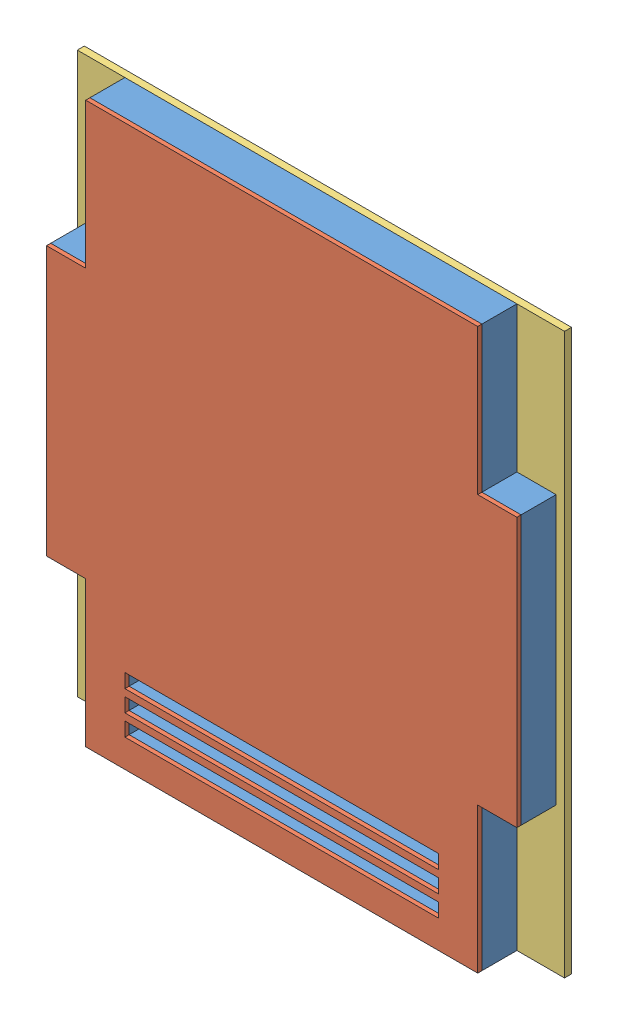
SolidWorks assembly Door, configuration Default. Lengths in mm.
Overall size (348 400 89.5).
5 component instances, 4 part files, 12 mates.
Components (placement in the parent):
- door wall poly-1: door wall poly [Default] at (21.682 231.8743 358.6656) size (336 400 25)
- door inner acrylic-1: door inner acrylic [Default] at (21.682 231.8743 383.6656) size (336 400 3)
- door acrylic outer-1: door acrylic outer [Default] at (136.6719 176.1454 353.6656) size (348 400 5)
- handle-1: handle [Default] at (171.9027 136.1173 445.2959) size (15 115 86.5)
- handle-2: handle [Default] at (-12.0973 136.1173 445.2959) size (15 115 86.5)
Mates (geometry in assembly coordinates):
- Coincident1: coincident: plane of door wall poly-1 through (-88.0973 419.9915 383.6656) normal (0 1 0); plane of door inner acrylic-1 through (-88.0973 419.9915 386.6656) normal (0 1 0)
- Coincident2: coincident: plane of door wall poly-1 through (219.9027 419.9915 383.6656) normal (1 0 0); plane of door inner acrylic-1 through (219.9027 419.9915 408.6656) normal (1 0 0)
- Coincident3: coincident: plane of door wall poly-1 through (21.682 231.8743 383.6656) normal (0 0 1); plane of door inner acrylic-1 through (21.682 231.8743 383.6656) normal (0 0 -1)
- Coincident5: coincident: plane of door wall poly-1 through (-88.0973 19.9915 383.6656) normal (0 -1 0); plane of door acrylic outer-1 through (-94.0973 19.9915 358.6656) normal (0 -1 0)
- Coincident6: coincident: plane of door wall poly-1 through (21.682 231.8743 358.6656) normal (0 0 -1); plane of door acrylic outer-1 through (136.6719 176.1454 358.6656) normal (0 0 1)
- Coincident7: coincident: plane of door wall poly-1 through (191.9027 49.9915 383.6656) normal (-1 0 0); plane of door acrylic outer-1 through (191.9027 49.9915 348.6656) normal (-1 0 0)
- Coincident8: coincident: plane of door inner acrylic-1 through (21.682 231.8743 383.6656) normal (0 0 -1); plane of handle-1 through (171.9027 229.9915 383.6656) normal (0 0 1)
- Coincident9: coincident: circle of door acrylic outer-1; cylinder of handle-1 through (171.9027 229.9915 319.6656) axis (0 0 1) radius 7.5
- Coincident10: coincident: circle of door acrylic outer-1; cylinder of handle-2 through (-12.0973 229.9915 319.6656) axis (0 0 1) radius 7.5
- Coincident11: coincident: circle of door acrylic outer-1; cylinder of handle-1 through (171.9027 129.9915 383.6656) axis (0 0 -1) radius 7.5
- Coincident12: coincident: circle of door acrylic outer-1; cylinder of handle-2 through (-12.0973 129.9915 383.6656) axis (0 0 -1) radius 7.5
- Coincident13: coincident: plane of door inner acrylic-1 through (21.682 231.8743 383.6656) normal (0 0 -1); plane of handle-2 through (-12.0973 129.9915 383.6656) normal (0 0 1)
